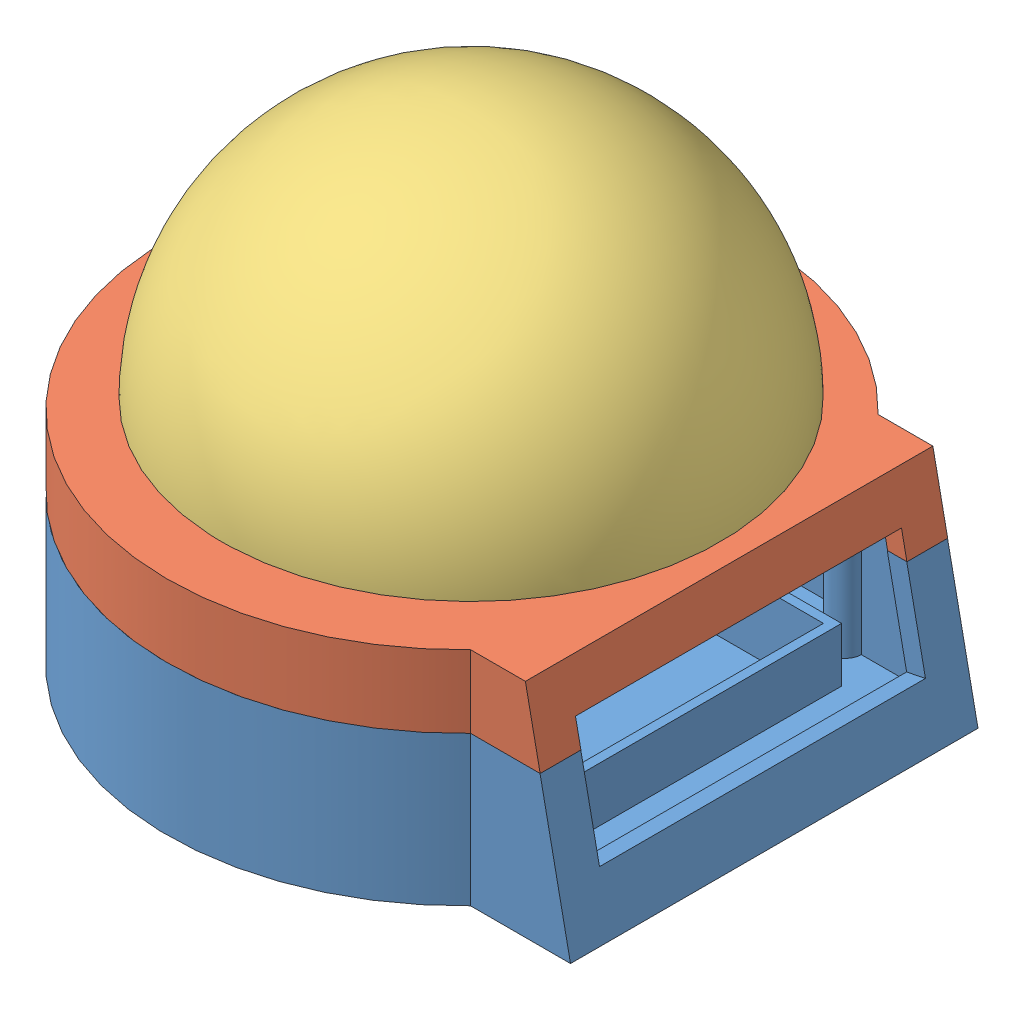
SolidWorks assembly Assem3, configuration Default. Lengths in mm.
Overall size (134 111.52 130).
7 component instances, 4 part files, 0 mates.
Components (placement in the parent):
- ButtonHousing2-1: ButtonHousing2 [Default] at (35.7044 45.7489 96.0117) size (134 38 130)
- ButtonHousingTop2-1: ButtonHousingTop2 [Default] at (35.7379 78.7482 96.0118) size (127.27 16 130)
- ButtonTop2-1: ButtonTop2 [Default] at (37.119 97.2667 95.3816) size (110 70 110)
- ButtonBase-1: ButtonBase [Default] at (4.3845 45.7468 124.5713) size (5 2.5 5)
- ButtonBase-2: ButtonBase [Default] at (83.7229 45.7538 132.0111) size (5 2.5 5)
- ButtonBase-3: ButtonBase [Default] at (82.9033 45.7375 59.8985) size (5 2.5 5)
- ButtonBase-4: ButtonBase [Default] at (2.3088 45.7465 69.0717) size (5 2.5 5)
